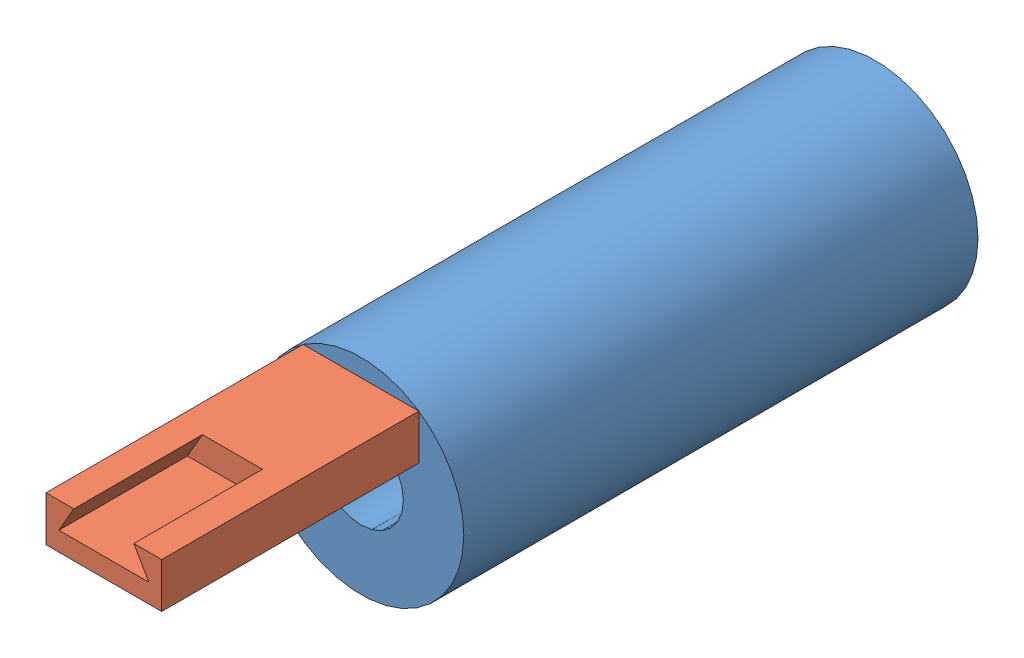
SolidWorks assembly rod_with_slider_holder_2500um, configuration Default. Lengths in mm.
Overall size (8 9.33 30).
2 component instances, 2 part files, 6 mates.
Components (placement in the parent):
- rod_stereotax_m4-1: rod_stereotax_m4 [Default] at (-18.071 14.8811 -20.5742) size (8 8 20)
- slider_3mm5-1: slider_3mm5 [female] at (-18.071 18.1883 4.4258) x (0 0 1) z (-1 0 0) size (10 3.77 4.5)
Mates (geometry in assembly coordinates):
- Coincident1: coincident aligned: plane of rod_stereotax_m4-1 through (-18.071 14.8811 -20.5742) normal (1 0 0); plane of slider-1 through (-18.071 17.8853 24.4258) normal (1 0 0)
- Coincident2: coincident anti-aligned: plane of rod_stereotax_m4-1 through (-18.071 14.8811 -0.5742) normal (0 0 1); plane of slider-1 through (-18.071 17.8853 9.4258) normal (0 0 -1)
- Tangent2: tangent anti-aligned: cylinder of rod_stereotax_m4-1 through (-18.071 14.8811 -20.5742) axis (0 0 -1) radius 1.65; plane of slider-1 through (-18.071 16.5311 29.4258) normal (0 -1 0)
- Coincident3: coincident anti-aligned: plane of rod_stereotax_m4-1 through (-18.071 14.8811 -0.5742) normal (0 0 1); plane of slider_3mm5-1 through (-18.071 18.1883 -0.5742) normal (0 0 -1)
- Coincident4: coincident anti-aligned: plane of slider_3mm5-1 through (-18.071 18.1883 4.4258) normal (-1 0 0); plane of rod_stereotax_m4-1 through (-18.071 14.8811 -20.5742) normal (1 0 0)
- Coincident5: coincident: circle of rod_stereotax_m4-1; point of slider_3mm5-1
